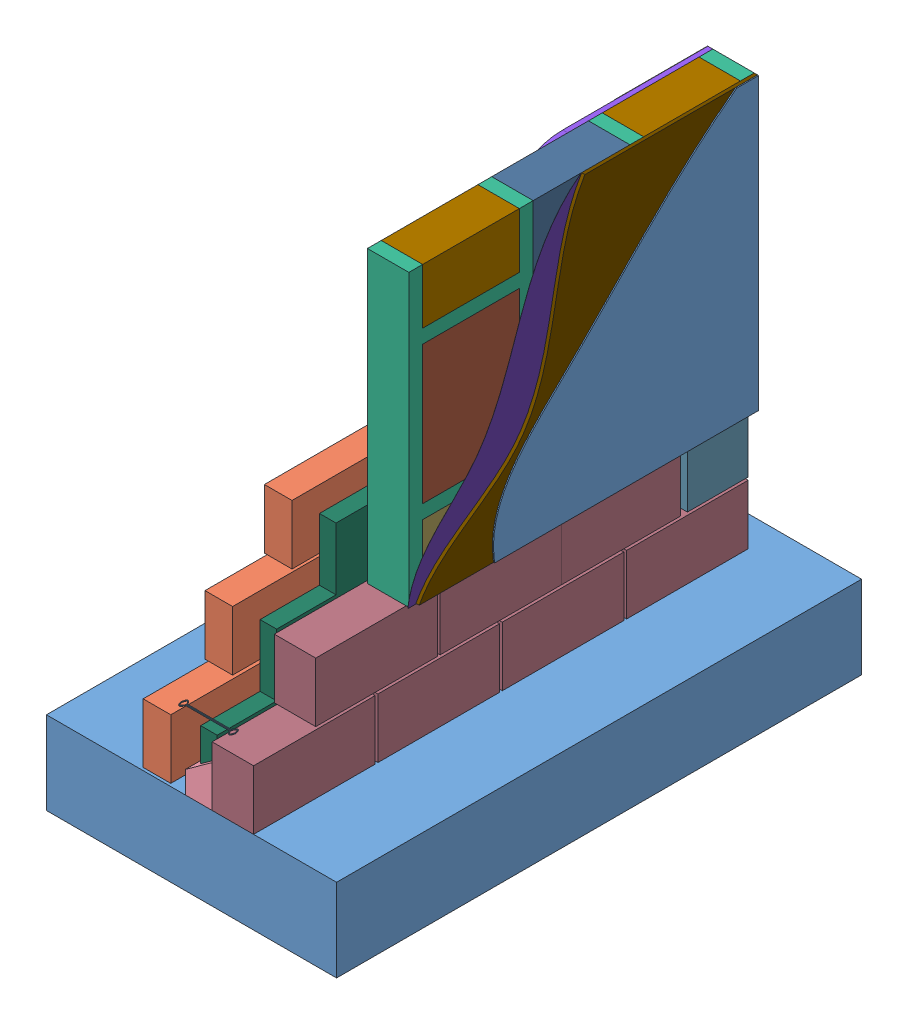
SolidWorks assembly Timber Framed Cavity Wall Completed Assembly, configuration Default. Lengths in mm.
Overall size (1050 1797.8 1900).
36 component instances, 19 part files, 84 mates.
Components (placement in the parent):
- Foundation 900 by 300-1: Foundation 900 by 300 [Default] at (-447.7084 -187.3596 -15.4042) size (1050 300 1900)
- Full Block-1: Full Block [Default] at (-97.7084 122.6404 494.5958) size (100 215 440)
- Full Block-2: Full Block [Default] at (-97.7084 122.4731 44.5972) size (100 215 440)
- Full Block-3: Full Block [Default] at (-97.7084 123.451 -405.3549) size (100 215 440)
- Full Block-4: Full Block [Default] at (-97.7084 122.228 -855.2798) size (100 215 440)
- Full Block-13: Full Block [Default] at (-98.893 348.7871 269.5925) size (100 215 440)
- Full Block-14: Full Block [Default] at (-98.893 348.7871 -180.4075) size (100 215 440)
- Full Block-15: Full Block [Default] at (-98.893 348.7871 -630.4075) size (100 215 440)
- Half Block-1: Half Block [Default] at (-98.893 348.7871 -855.4075) size (100 215 215)
- Full Block-22: Full Block [Default] at (-98.893 573.7871 54.5925) size (100 215 440)
- Full Block-23: Full Block [Default] at (-98.893 573.7871 -395.4075) size (100 215 440)
- Full Block-24: Full Block [Default] at (-98.893 573.7871 -845.4075) size (100 215 440)
- Concrete Fill-1: Concrete Fill [Default] at (57.582 116.6984 -855.4042) size (97 150 1790)
- Cavity Tie-2: Cavity Tie [Default] at (80.9007 337.6404 876.5329) size (200.28 4.57 35.23)
- Timber Frame-1: Timber Frame [Default] at (244.3924 585.4412 -859.895) size (150 1050 1250)
- Breather Membrane-1: Breather Membrane [Default] at (151.3924 1085.4412 -334.895) x (0 0 1) z (-1 0 0) size (915.85 1050 1)
- Ply for Timberframe-1: Ply for Timberframe [Default] at (160.3924 1085.4412 -334.895) x (0 0 1) z (-1 0 0) size (1050 1050 18)
- block insulation tf-1: block insulation tf [Default] at (244.3924 1510.4412 165.105) x (0 0 1) z (-1 0 0) size (350 200 150)
- block insulation4-1: block insulation4 [Default] at (244.3924 1485.4412 -234.895) size (150 250 350)
- block insulation2-1: block insulation2 [Default] at (244.3924 1110.4412 165.105) size (150 500 350)
- block insulation3-2: block insulation3 [Default] at (244.3924 710.4412 165.105) size (150 200 350)
- 6 Inch Block Timberframing-2: 6 Inch Block Timberframing [Default] at (226.9579 220.1404 714.5958) x (0 0 -1) z (1 0 0) size (440 215 150)
- 6 Inch Block Timberframing-3: 6 Inch Block Timberframing [Default] at (226.9579 220.1404 264.5958) x (0 0 1) z (-1 0 0) size (440 215 150)
- 6 Inch Block Timberframing-4: 6 Inch Block Timberframing [Default] at (226.9579 220.1404 -185.4042) x (0 0 1) z (-1 0 0) size (440 215 150)
- 6 Inch Block Timberframing-5: 6 Inch Block Timberframing [Default] at (226.9579 220.1404 -635.4042) x (0 0 -1) z (1 0 0) size (440 215 150)
- 6 Inch Block Timberframing-6: 6 Inch Block Timberframing [Default] at (226.9579 445.1404 489.5925) x (0 0 -1) z (1 0 0) size (440 215 150)
- 6 Inch Block Timberframing-7: 6 Inch Block Timberframing [Default] at origin size (440 215 150)
- 6 Inch Block Timberframing-8: 6 Inch Block Timberframing [Default] at (226.9579 445.1404 39.5925) x (0 0 -1) z (1 0 0) size (440 215 150)
- 6 Inch Block Timberframing-9: 6 Inch Block Timberframing [Default] at (226.9579 445.1404 -390.4075) x (0 0 1) z (-1 0 0) size (440 215 150)
- Half 6 Inch Block Timberframing-1: Half 6 Inch Block Timberframing [Default] at (226.9579 445.1404 -745.4042) x (0 0 1) z (-1 0 0) size (220 215 150)
- Cavity Insulation-3: Cavity Insulation [Default] at (120.3924 447.8624 35.5693) x (0 0 1) z (-1 0 0) size (1770 675 60)
- Galvanised Straping-1: Galvanised Straping [Default] at (151.3924 1015.4861 -66.5621) x (0 0 1) z (-1 0 0) size (30 226.7 178)
- Polythene Layer-1: Polythene Layer [Default] at (319.3924 1183.5171 -230.8618) x (0 0 -1) z (1 0 0) size (1250 1050 0.25)
- Plasterboard-1: Plasterboard [Default] at (319.3924 985.4412 -234.895) x (0 0 -1) z (1 0 0) size (1224.51 1050 12)
- Int Plaster-1: Int Plaster [Default] at (331.3924 1185.4412 -234.895) x (0 0 -1) z (1 0 0) size (988.51 1050 4)
- block insulation tf-3: block insulation tf [Default] at (244.3924 1510.4412 -634.895) x (0 0 1) z (-1 0 0) size (350 200 150)
Mates (geometry in assembly coordinates):
- Coincident1: coincident aligned: plane of Foundation 900 by 300-1 through (-447.7084 112.6404 934.5958) normal (0 0 1); plane of Full Block-1 through (-97.7084 337.6404 934.5958) normal (0 0 1)
- Distance1: distance = 10 mm: line of Full Block-1 through (-97.7084 122.6404 934.5958) axis (1 0 0); line of Foundation 900 by 300-1 through (602.2916 112.6404 934.5958) axis (-1 0 0)
- Distance2: distance = 350 mm: line of Foundation 900 by 300-1 through (-447.7084 112.6404 934.5958) axis (0 -1 0); line of Full Block-1 through (-97.7084 337.6404 934.5958) axis (0 -1 0)
- Coincident4: coincident aligned: plane of Full Block-1 through (-97.7084 122.6404 934.5958) normal (-1 0 0); plane of Full Block-2 through (-97.7084 122.4731 484.5972) normal (-1 0 0)
- Distance3: distance = 10 mm: line of Full Block-2 through (2.2916 337.4731 484.5972) axis (-1 0 0); line of Full Block-1 through (2.2916 337.6404 494.5958) axis (-1 0 0)
- Coincident7: coincident aligned: plane of Full Block-2 through (-97.7084 122.4731 484.5972) normal (-1 0 0); plane of Full Block-3 through (-97.7084 123.451 34.6451) normal (-1 0 0)
- Distance5: distance = 10 mm: line of Full Block-2 through (2.2916 337.4731 44.5972) axis (-1 0 0); line of Full Block-3 through (2.2916 338.451 34.6451) axis (-1 0 0)
- Coincident9: coincident aligned: plane of Full Block-3 through (-97.7084 123.451 34.6451) normal (-1 0 0); plane of Full Block-4 through (-97.7084 122.228 -415.2798) normal (-1 0 0)
- Distance6: distance = 10 mm: line of Full Block-4 through (2.2916 337.228 -415.2798) axis (-1 0 0); line of Full Block-3 through (2.2916 338.451 -405.3549) axis (-1 0 0)
- Distance8: distance = 215 mm: line of Full Block-13 through (-98.893 563.7871 709.5925) axis (0 -1 0); line of Full Block-1 through (-97.7084 337.6404 494.5958) axis (0 -1 0)
- Coincident18: coincident aligned: plane of Full Block-13 through (-98.893 348.7871 709.5925) normal (-1 0 0); plane of Full Block-14 through (-98.893 348.7871 259.5925) normal (-1 0 0)
- Distance10: distance = 10 mm: line of Full Block-14 through (-98.893 563.7871 259.5925) axis (0 -1 0); line of Full Block-13 through (-98.893 563.7871 269.5925) axis (0 -1 0)
- Coincident23: coincident aligned: plane of Full Block-13 through (-98.893 563.7871 709.5925) normal (0 1 0); plane of Full Block-14 through (-98.893 563.7871 259.5925) normal (0 1 0)
- Coincident24: coincident aligned: plane of Full Block-14 through (-98.893 348.7871 259.5925) normal (-1 0 0); plane of Full Block-15 through (-98.893 348.7871 -190.4075) normal (-1 0 0)
- Distance14: distance = 10 mm: line of Full Block-14 through (1.107 563.7871 -180.4075) axis (-1 0 0); line of Full Block-15 through (1.107 563.7871 -190.4075) axis (-1 0 0)
- Coincident26: coincident aligned: plane of Full Block-14 through (-98.893 563.7871 259.5925) normal (0 1 0); plane of Full Block-15 through (-98.893 563.7871 -190.4075) normal (0 1 0)
- Coincident27: coincident aligned: plane of Full Block-15 through (-98.893 348.7871 -190.4075) normal (-1 0 0); plane of Half Block-1 through (-98.893 348.7871 -640.4075) normal (-1 0 0)
- Coincident28: coincident aligned: plane of Full Block-15 through (-98.893 563.7871 -190.4075) normal (0 1 0); plane of Half Block-1 through (-98.893 563.7871 -640.4075) normal (0 1 0)
- Distance15: distance = 10 mm: line of Full Block-15 through (-98.893 563.7871 -630.4075) axis (0 -1 0); line of Half Block-1 through (-98.893 563.7871 -640.4075) axis (0 -1 0)
- Coincident43: coincident anti-aligned: plane of Foundation 900 by 300-1 through (-447.7084 112.6404 934.5958) normal (0 1 0); plane of Concrete Fill-1 through (151.9579 112.6404 934.5958) normal (0 -1 0)
- Coincident50: coincident anti-aligned: plane of Timber Frame-1 through (169.3924 560.4412 390.105) normal (-1 0 0); plane of Ply for Timberframe-1 through (169.3924 1610.4412 -859.895) normal (1 0 0)
- Coincident51: coincident aligned: line of Timber Frame-1 through (169.3924 1610.4412 -859.895) axis (0 -1 0); line of Ply for Timberframe-1 through (169.3924 1610.4412 -859.895) axis (0 -1 0)
- Coincident52: coincident anti-aligned: plane of Breather Membrane-1 through (151.3924 1094.4994 -210.6911) normal (1 0 0); plane of Ply for Timberframe-1 through (151.3924 1610.4412 -859.895) normal (-1 0 0)
- Coincident54: coincident aligned: line of Breather Membrane-1 through (151.3924 1610.4412 -859.895) axis (0 -1 0); line of Ply for Timberframe-1 through (151.3924 1610.4412 -859.895) axis (0 -1 0)
- Coincident55: coincident anti-aligned: line of Timber Frame-1 through (319.3924 1610.4412 -859.895) axis (-1 0 0); line of Ply for Timberframe-1 through (151.3924 1610.4412 -859.895) axis (1 0 0)
- Coincident56: coincident aligned: line of Breather Membrane-1 through (150.3924 560.4412 -859.895) axis (1 0 0); line of Ply for Timberframe-1 through (151.3924 560.4412 -859.895) axis (1 0 0)
- Coincident57: coincident: plane of Timber Frame-1 through (169.3924 560.4412 390.105) normal (-1 0 0); plane of block insulation tf-1 through (169.3924 1610.4412 -9.895) normal (-1 0 0)
- Coincident58: coincident: line of Timber Frame-1 through (169.3924 1410.4412 340.105) axis (0 0 -1); line of block insulation tf-1 through (169.3924 1410.4412 -9.895) axis (0 0 1)
- Coincident59: coincident: line of Timber Frame-1 through (169.3924 1610.4412 340.105) axis (0 -1 0); line of block insulation tf-1 through (169.3924 1410.4412 340.105) axis (0 1 0)
- Coincident60: coincident aligned: plane of Timber Frame-1 through (169.3924 560.4412 390.105) normal (-1 0 0); plane of block insulation4-1 through (169.3924 1610.4412 -59.895) normal (-1 0 0)
- Coincident61: coincident anti-aligned: plane of Timber Frame-1 through (169.3924 1360.4412 -59.895) normal (0 1 0); plane of block insulation4-1 through (319.3924 1360.4412 -409.895) normal (0 -1 0)
- Coincident62: coincident: plane of Timber Frame-1 through (319.3924 1610.4412 -409.895) normal (0 0 1); plane of block insulation4-1 through (319.3924 1360.4412 -409.895) normal (0 0 -1)
- Coincident70: coincident aligned: plane of Timber Frame-1 through (169.3924 560.4412 390.105) normal (-1 0 0); plane of block insulation2-1 through (169.3924 1360.4412 340.105) normal (-1 0 0)
- Coincident71: coincident anti-aligned: plane of Timber Frame-1 through (319.3924 1610.4412 340.105) normal (0 0 -1); plane of block insulation2-1 through (319.3924 860.4412 340.105) normal (0 0 1)
- Coincident72: coincident anti-aligned: plane of Timber Frame-1 through (169.3924 860.4412 340.105) normal (0 1 0); plane of block insulation2-1 through (319.3924 860.4412 -9.895) normal (0 -1 0)
- Coincident73: coincident aligned: plane of Timber Frame-1 through (319.3924 560.4412 390.105) normal (1 0 0); plane of block insulation3-2 through (319.3924 810.4412 340.105) normal (1 0 0)
- Coincident74: coincident anti-aligned: plane of Timber Frame-1 through (319.3924 610.4412 390.105) normal (0 1 0); plane of block insulation3-2 through (319.3924 610.4412 -9.895) normal (0 -1 0)
- Coincident75: coincident: line of Timber Frame-1 through (319.3924 810.4412 340.105) axis (0 -1 0); line of block insulation3-2 through (319.3924 810.4412 340.105) axis (0 -1 0)
- Parallel2: parallel anti-aligned: plane of Foundation 900 by 300-1 through (-447.7084 112.6404 934.5958) normal (0 0 1); plane of 6 Inch Block Timberframing-2 through (301.9579 327.6404 494.5958) normal (0 0 -1)
- Coincident86: coincident aligned: line of Foundation 900 by 300-1 through (602.2916 112.6404 934.5958) axis (-1 0 0); line of 6 Inch Block Timberframing-2 through (301.9579 112.6404 934.5958) axis (-1 0 0)
- Distance17: distance = 150 mm: line of 6 Inch Block Timberframing-2 through (151.9579 112.6404 494.5958) axis (0 0 1); line of Full Block-1 through (2.2916 122.6404 934.5958) axis (0 0 -1)
- Parallel3: parallel anti-aligned: plane of 6 Inch Block Timberframing-2 through (301.9579 327.6404 494.5958) normal (0 0 -1); plane of 6 Inch Block Timberframing-3 through (151.9579 327.6404 484.5958) normal (0 0 1)
- Coincident90: coincident anti-aligned: plane of Foundation 900 by 300-1 through (-447.7084 112.6404 934.5958) normal (0 1 0); plane of 6 Inch Block Timberframing-3 through (301.9579 112.6404 484.5958) normal (0 -1 0)
- Parallel4: parallel anti-aligned: line of 6 Inch Block Timberframing-2 through (301.9579 112.6404 494.5958) axis (0 0 1); line of 6 Inch Block Timberframing-3 through (301.9579 112.6404 484.5958) axis (0 0 -1)
- Distance18: distance = 10 mm: line of 6 Inch Block Timberframing-3 through (301.9579 327.6404 484.5958) axis (-1 0 0); line of 6 Inch Block Timberframing-2 through (151.9579 327.6404 494.5958) axis (1 0 0)
- Coincident93: coincident anti-aligned: line of 6 Inch Block Timberframing-2 through (151.9579 327.6404 494.5958) axis (0 0 1); line of 6 Inch Block Timberframing-3 through (151.9579 327.6404 484.5958) axis (0 0 -1)
- Coincident95: coincident anti-aligned: plane of Foundation 900 by 300-1 through (-447.7084 112.6404 934.5958) normal (0 1 0); plane of 6 Inch Block Timberframing-4 through (301.9579 112.6404 34.5958) normal (0 -1 0)
- Distance22: distance = 10 mm: line of 6 Inch Block Timberframing-4 through (301.9579 327.6404 34.5958) axis (-1 0 0); line of 6 Inch Block Timberframing-3 through (301.9579 327.6404 44.5958) axis (-1 0 0)
- Coincident100: coincident aligned: line of 6 Inch Block Timberframing-3 through (301.9579 327.6404 484.5958) axis (0 0 -1); line of 6 Inch Block Timberframing-4 through (301.9579 327.6404 34.5958) axis (0 0 -1)
- Parallel5: parallel anti-aligned: plane of 6 Inch Block Timberframing-4 through (301.9579 112.6404 34.5958) normal (1 0 0); plane of 6 Inch Block Timberframing-5 through (151.9579 112.6404 -855.4042) normal (-1 0 0)
- Coincident102: coincident aligned: plane of 6 Inch Block Timberframing-4 through (301.9579 327.6404 34.5958) normal (0 1 0); plane of 6 Inch Block Timberframing-5 through (151.9579 327.6404 -855.4042) normal (0 1 0)
- Coincident103: coincident aligned: plane of 6 Inch Block Timberframing-4 through (301.9579 327.6404 34.5958) normal (0 1 0); plane of 6 Inch Block Timberframing-5 through (151.9579 327.6404 -855.4042) normal (0 1 0)
- Coincident104: coincident aligned: plane of 6 Inch Block Timberframing-4 through (301.9579 327.6404 34.5958) normal (0 1 0); plane of 6 Inch Block Timberframing-5 through (151.9579 327.6404 -855.4042) normal (0 1 0)
- Distance23: distance = 10 mm: line of 6 Inch Block Timberframing-4 through (301.9579 327.6404 -405.4042) axis (-1 0 0); line of 6 Inch Block Timberframing-5 through (151.9579 327.6404 -415.4042) axis (1 0 0)
- Coincident106: coincident aligned: plane of 6 Inch Block Timberframing-4 through (301.9579 112.6404 34.5958) normal (1 0 0); plane of 6 Inch Block Timberframing-5 through (301.9579 112.6404 -855.4042) normal (1 0 0)
- Parallel6: parallel anti-aligned: plane of 6 Inch Block Timberframing-2 through (301.9579 112.6404 494.5958) normal (1 0 0); plane of 6 Inch Block Timberframing-6 through (151.9579 337.6404 269.5925) normal (-1 0 0)
- Coincident108: coincident aligned: plane of Full Block-13 through (-98.893 563.7871 709.5925) normal (0 0 1); plane of 6 Inch Block Timberframing-6 through (301.9579 552.6404 709.5925) normal (0 0 1)
- Distance24: distance = 10 mm: line of 6 Inch Block Timberframing-6 through (301.9579 337.6404 269.5925) axis (0 0 1); line of 6 Inch Block Timberframing-3 through (301.9579 327.6404 484.5958) axis (0 0 -1)
- Coincident111: coincident aligned: plane of Full Block-13 through (-98.893 563.7871 709.5925) normal (0 0 1); plane of 6 Inch Block Timberframing-6 through (301.9579 552.6404 709.5925) normal (0 0 1)
- Coincident112: coincident anti-aligned: plane of Concrete Fill-1 through (151.9579 112.6404 934.5958) normal (1 0 0); plane of 6 Inch Block Timberframing-2 through (151.9579 112.6404 494.5958) normal (-1 0 0)
- Coincident114: coincident aligned: plane of 6 Inch Block Timberframing-6 through (151.9579 552.6404 269.5925) normal (0 1 0); plane of 6 Inch Block Timberframing-8 through (151.9579 552.6404 -180.4075) normal (0 1 0)
- Distance25: distance = 10 mm: line of 6 Inch Block Timberframing-8 through (151.9579 552.6404 259.5925) axis (1 0 0); line of 6 Inch Block Timberframing-6 through (151.9579 552.6404 269.5925) axis (1 0 0)
- Coincident116: coincident aligned: line of 6 Inch Block Timberframing-6 through (151.9579 552.6404 269.5925) axis (0 0 1); line of 6 Inch Block Timberframing-8 through (151.9579 552.6404 -180.4075) axis (0 0 1)
- Distance27: distance = 10 mm anti-aligned: plane of 6 Inch Block Timberframing-9 through (151.9579 552.6404 -170.4075) normal (0 0 1); plane of 6 Inch Block Timberframing-8 through (301.9579 552.6404 -180.4075) normal (0 0 -1)
- Coincident122: coincident anti-aligned: line of 6 Inch Block Timberframing-8 through (301.9579 552.6404 -180.4075) axis (0 0 1); line of 6 Inch Block Timberframing-9 through (301.9579 552.6404 -170.4075) axis (0 0 -1)
- Coincident125: coincident aligned: plane of 6 Inch Block Timberframing-5 through (301.9579 327.6404 -855.4042) normal (0 0 -1); plane of Half 6 Inch Block Timberframing-1 through (151.9579 552.6404 -855.4042) normal (0 0 -1)
- Coincident126: coincident aligned: plane of 6 Inch Block Timberframing-9 through (301.9579 552.6404 -170.4075) normal (0 1 0); plane of Half 6 Inch Block Timberframing-1 through (301.9579 552.6404 -635.4042) normal (0 1 0)
- Coincident139: coincident aligned: plane of Half 6 Inch Block Timberframing-1 through (151.9579 337.6404 -635.4042) normal (-1 0 0); plane of 6 Inch Block Timberframing-5 through (151.9579 112.6404 -855.4042) normal (-1 0 0)
- Coincident140: coincident aligned: plane of 6 Inch Block Timberframing-9 through (151.9579 337.6404 -170.4075) normal (-1 0 0); plane of 6 Inch Block Timberframing-4 through (151.9579 112.6404 34.5958) normal (-1 0 0)
- Coincident145: coincident anti-aligned: plane of Breather Membrane-1 through (150.3924 1094.4994 -210.6911) normal (-1 0 0); plane of Cavity Insulation-3 through (150.3924 787.6404 -855.4042) normal (1 0 0)
- Coincident146: coincident anti-aligned: plane of Foundation 900 by 300-1 through (-447.7084 112.6404 934.5958) normal (0 1 0); plane of Cavity Insulation-3 through (90.3924 112.6404 914.5958) normal (0 -1 0)
- Coincident147: coincident aligned: plane of Half 6 Inch Block Timberframing-1 through (151.9579 552.6404 -855.4042) normal (0 0 -1); plane of Cavity Insulation-3 through (90.3924 112.6404 -855.4042) normal (0 0 -1)
- Coincident148: coincident anti-aligned: plane of Ply for Timberframe-1 through (151.3924 1610.4412 -859.895) normal (-1 0 0); plane of Galvanised Straping-1 through (151.3924 1015.4861 -36.5621) normal (1 0 0)
- Coincident149: coincident anti-aligned: plane of Full Block-23 through (-98.893 788.7871 44.5925) normal (0 1 0); plane of Galvanised Straping-1 through (63.3924 788.7871 -36.5621) normal (0 -1 0)
- Coincident150: coincident anti-aligned: plane of Timber Frame-1 through (319.3924 560.4412 390.105) normal (1 0 0); plane of Polythene Layer-1 through (319.3924 1065.5865 59.8661) normal (-1 0 0)
- Parallel10: parallel anti-aligned: plane of Timber Frame-1 through (319.3924 560.4412 390.105) normal (1 0 0); plane of Plasterboard-1 through (319.3924 999.465 -60.6316) normal (-1 0 0)
- Coincident152: coincident aligned: line of Timber Frame-1 through (319.3924 560.4412 390.105) axis (0 0 -1); line of Plasterboard-1 through (319.3924 560.4412 364.6186) axis (0 0 -1)
- Coincident153: coincident aligned: line of Timber Frame-1 through (319.3924 560.4412 -859.895) axis (0 1 0); line of Plasterboard-1 through (319.3924 560.4412 -859.895) axis (0 1 0)
- Coincident154: coincident anti-aligned: plane of Plasterboard-1 through (331.3924 999.465 -60.6316) normal (1 0 0); plane of Int Plaster-1 through (331.3924 1134.184 -269.9587) normal (-1 0 0)
- Coincident155: coincident aligned: line of Plasterboard-1 through (331.3924 560.4412 364.6186) axis (0 0 -1); line of Int Plaster-1 through (331.3924 560.4412 95.3862) axis (0 0 -1)
- Coincident156: coincident aligned: line of Plasterboard-1 through (331.3924 560.4412 -859.895) axis (0 1 0); line of Int Plaster-1 through (331.3924 560.4412 -859.895) axis (0 1 0)
- Coincident158: coincident anti-aligned: plane of Ply for Timberframe-1 through (169.3924 1610.4412 -859.895) normal (1 0 0); plane of block insulation tf-3 through (169.3924 1610.4412 -809.895) normal (-1 0 0)
- Coincident159: coincident anti-aligned: plane of Timber Frame-1 through (169.3924 1610.4412 -809.895) normal (0 0 1); plane of block insulation tf-3 through (169.3924 1410.4412 -809.895) normal (0 0 -1)
- Coincident160: coincident anti-aligned: plane of Timber Frame-1 through (169.3924 1410.4412 -459.895) normal (0 1 0); plane of block insulation tf-3 through (169.3924 1410.4412 -459.895) normal (0 -1 0)
